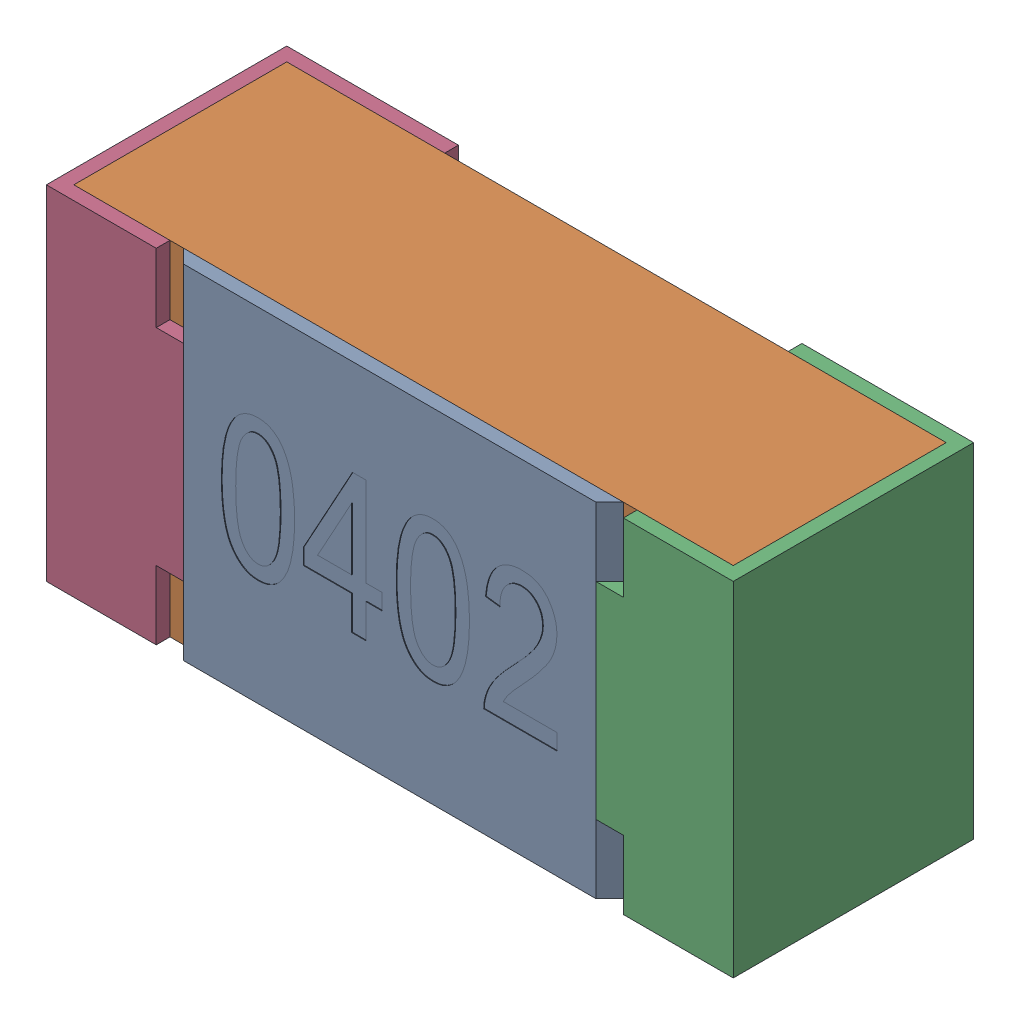
SolidWorks assembly R6, configuration Standard. Lengths in mm.
Overall size (1 0.5 0.35).
5 component instances, 4 part files, 0 mates.
Components (placement in the parent):
- R6-subassembly-1-1: R6-subassembly-1 [Standard] at (6.7001 -14.9 0) x (1 0 0) z (0 0 1) size (1 0.5 0.35)
  - User Library-R_0402-1: User Library-R_0402 [Standard] at origin size (0.64 0.5 0.02)
  - User Library-R_0402-1-1: User Library-R_0402-1 [Standard] at origin size (0.96 0.5 0.31)
  - User Library-R_0402-2-1: User Library-R_0402-2 [Standard] at origin size (0.25 0.5 0.35)
  - User Library-R_0402-3-1: User Library-R_0402-3 [Standard] at origin size (0.25 0.5 0.35)
